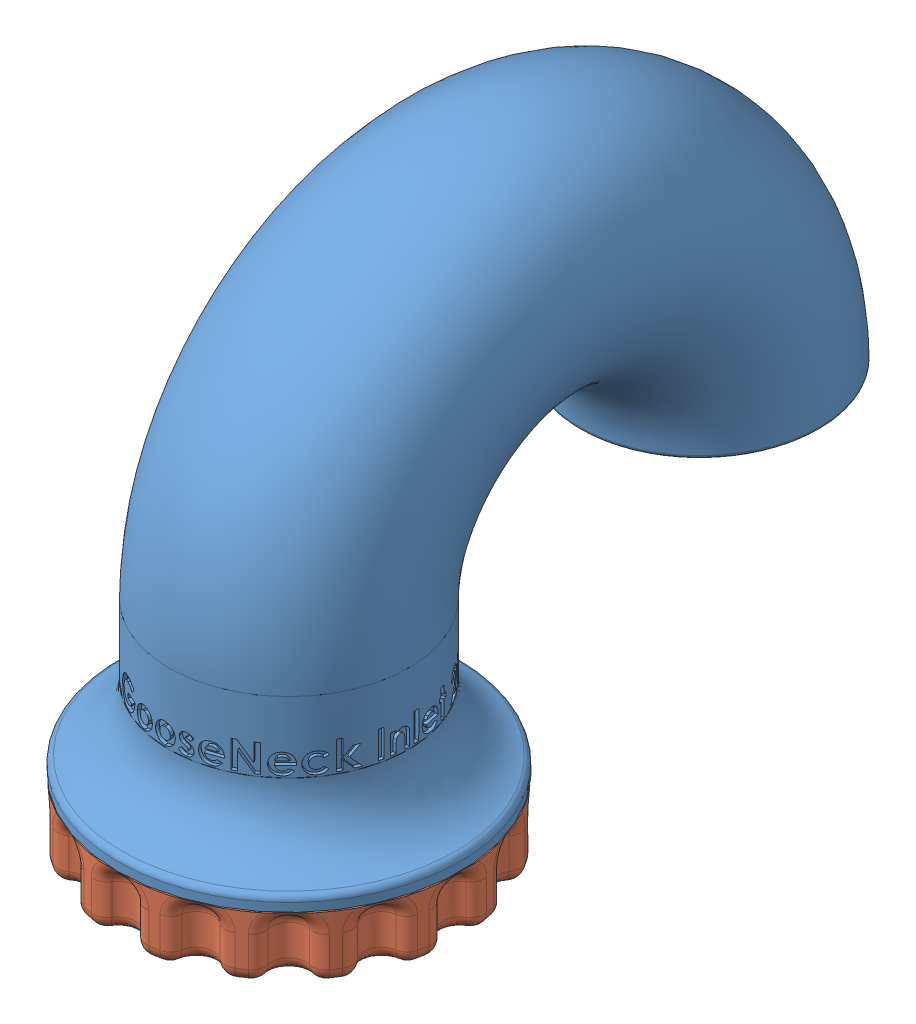
SolidWorks assembly Roof Electrical Connection, configuration Default. Lengths in mm.
Overall size (63.99 101.76 132.11).
2 component instances, 2 part files, 5 mates.
Components (placement in the parent):
- Goosneck Electrical Inlet V1-1: Goosneck Electrical Inlet V1 [Default] at origin size (63.5 101.07 131.86)
- Roof Electrical Connection Nut-1: Roof Electrical Connection Nut [Default] at (0 -2.54 0) x (-1 0 0) z (0 -1 0) size (63.99 63.99 14.73)
Mates (geometry in assembly coordinates):
- Coincident1: coordinate: point of Electrical Connection-1
- InPlace1: in place: plane of Goosneck Electrical Inlet V1-1 through (0 -2.54 0) normal (0 -1 0); plane of Roof Electrical Connection Nut-1 through (0 -2.54 0) normal (0 -1 0); moOrthogonalPlaneRef_w of Goosneck Electrical Inlet V1-1 through (0 -2.54 0) normal (0 -1 0); plane of Roof Electrical Connection Nut-1 through (0 -2.54 0) normal (0 0 -1); plane of Goosneck Electrical Inlet V1-1 through (0 -2.54 0) normal (0 -1 0); plane of Roof Electrical Connection Nut-1 through (0 -2.54 0) normal (-1 0 0); plane of Goosneck Electrical Inlet V1-1 through (0 -2.54 0) normal (0 -1 0); unknown of Roof Electrical Connection Nut-1
- Coincident2: coincident aligned: plane of ?; plane of ?
- Coincident3: coincident aligned: moOrthogonalPlaneRef_w of Electrical Connection-1 through (0 -2.54 0) normal (0 0 -1); plane of Roof Electrical Connection Nut-1 through (0 -2.54 0) normal (0 0 -1)
- Coincident4: coincident anti-aligned: moOrthogonalPlaneRef_w of Electrical Connection-1 through (0 -2.54 0) normal (1 0 0); plane of Roof Electrical Connection Nut-1 through (0 -2.54 0) normal (-1 0 0)
